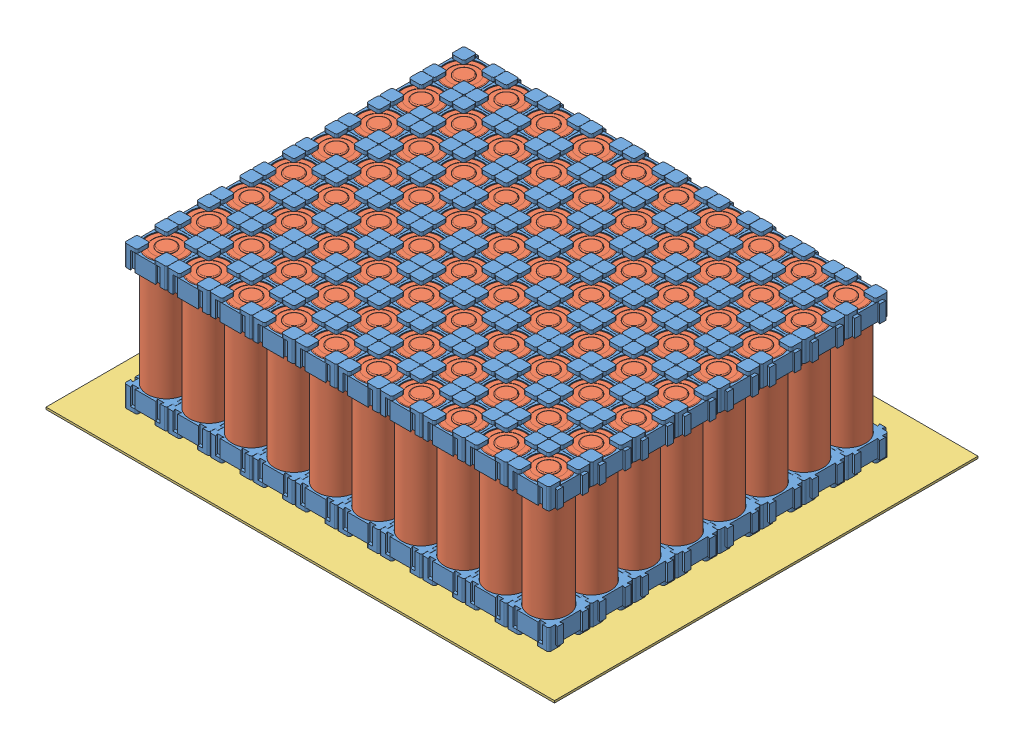
SolidWorks assembly BatteyPackOneLevel, configuration Default. Lengths in mm.
Overall size (245.5 69.3 204.9).
321 component instances, 3 part files, 4 mates.
Components (placement in the parent):
- SingleCellAssembly-2: SingleCellAssembly [Default] at (-432.012 -66.15 -21.6) x (0 0 1) z (1 0 0) size (21.6 68.3 21.6)
  - 1P Holder-1: 1P Holder [Default] at (11.5 -56.15 60.678) x (0 0 -1) z (-1 0 0) size (21.6 10 21.6)
  - 1P Holder-2: 1P Holder [Default] at (11.5 -7.85 60.678) size (21.6 10 21.6)
  - 18650 battery-2: 18650 battery [默认] at (40.3744 0.35 45.406) x (1 0 0) z (0 -1 0) size (18.2 18.2 65.15)
- SingleCellAssembly-374: SingleCellAssembly [Default] at (-411.712 -66.15 -21.6) x (0 0 1) z (1 0 0) size (21.6 68.3 21.6)
  - 1P Holder-1: 1P Holder [Default] at (11.5 -56.15 60.678) x (0 0 -1) z (-1 0 0) size (21.6 10 21.6)
  - 1P Holder-2: 1P Holder [Default] at (11.5 -7.85 60.678) size (21.6 10 21.6)
  - 18650 battery-2: 18650 battery [默认] at (40.3744 0.35 45.406) x (1 0 0) z (0 -1 0) size (18.2 18.2 65.15)
- SingleCellAssembly-375: SingleCellAssembly [Default] at (-391.412 -66.15 -21.6) x (0 0 1) z (1 0 0) size (21.6 68.3 21.6)
  - 1P Holder-1: 1P Holder [Default] at (11.5 -56.15 60.678) x (0 0 -1) z (-1 0 0) size (21.6 10 21.6)
  - 1P Holder-2: 1P Holder [Default] at (11.5 -7.85 60.678) size (21.6 10 21.6)
  - 18650 battery-2: 18650 battery [默认] at (40.3744 0.35 45.406) x (1 0 0) z (0 -1 0) size (18.2 18.2 65.15)
- SingleCellAssembly-376: SingleCellAssembly [Default] at (-371.112 -66.15 -21.6) x (0 0 1) z (1 0 0) size (21.6 68.3 21.6)
  - 1P Holder-1: 1P Holder [Default] at (11.5 -56.15 60.678) x (0 0 -1) z (-1 0 0) size (21.6 10 21.6)
  - 1P Holder-2: 1P Holder [Default] at (11.5 -7.85 60.678) size (21.6 10 21.6)
  - 18650 battery-2: 18650 battery [默认] at (40.3744 0.35 45.406) x (1 0 0) z (0 -1 0) size (18.2 18.2 65.15)
- SingleCellAssembly-377: SingleCellAssembly [Default] at (-350.812 -66.15 -21.6) x (0 0 1) z (1 0 0) size (21.6 68.3 21.6)
  - 1P Holder-1: 1P Holder [Default] at (11.5 -56.15 60.678) x (0 0 -1) z (-1 0 0) size (21.6 10 21.6)
  - 1P Holder-2: 1P Holder [Default] at (11.5 -7.85 60.678) size (21.6 10 21.6)
  - 18650 battery-2: 18650 battery [默认] at (40.3744 0.35 45.406) x (1 0 0) z (0 -1 0) size (18.2 18.2 65.15)
- SingleCellAssembly-378: SingleCellAssembly [Default] at (-330.512 -66.15 -21.6) x (0 0 1) z (1 0 0) size (21.6 68.3 21.6)
  - 1P Holder-1: 1P Holder [Default] at (11.5 -56.15 60.678) x (0 0 -1) z (-1 0 0) size (21.6 10 21.6)
  - 1P Holder-2: 1P Holder [Default] at (11.5 -7.85 60.678) size (21.6 10 21.6)
  - 18650 battery-2: 18650 battery [默认] at (40.3744 0.35 45.406) x (1 0 0) z (0 -1 0) size (18.2 18.2 65.15)
- SingleCellAssembly-379: SingleCellAssembly [Default] at (-310.212 -66.15 -21.6) x (0 0 1) z (1 0 0) size (21.6 68.3 21.6)
  - 1P Holder-1: 1P Holder [Default] at (11.5 -56.15 60.678) x (0 0 -1) z (-1 0 0) size (21.6 10 21.6)
  - 1P Holder-2: 1P Holder [Default] at (11.5 -7.85 60.678) size (21.6 10 21.6)
  - 18650 battery-2: 18650 battery [默认] at (40.3744 0.35 45.406) x (1 0 0) z (0 -1 0) size (18.2 18.2 65.15)
- SingleCellAssembly-380: SingleCellAssembly [Default] at (-289.912 -66.15 -21.6) x (0 0 1) z (1 0 0) size (21.6 68.3 21.6)
  - 1P Holder-1: 1P Holder [Default] at (11.5 -56.15 60.678) x (0 0 -1) z (-1 0 0) size (21.6 10 21.6)
  - 1P Holder-2: 1P Holder [Default] at (11.5 -7.85 60.678) size (21.6 10 21.6)
  - 18650 battery-2: 18650 battery [默认] at (40.3744 0.35 45.406) x (1 0 0) z (0 -1 0) size (18.2 18.2 65.15)
- SingleCellAssembly-381: SingleCellAssembly [Default] at (-269.612 -66.15 -21.6) x (0 0 1) z (1 0 0) size (21.6 68.3 21.6)
  - 1P Holder-1: 1P Holder [Default] at (11.5 -56.15 60.678) x (0 0 -1) z (-1 0 0) size (21.6 10 21.6)
  - 1P Holder-2: 1P Holder [Default] at (11.5 -7.85 60.678) size (21.6 10 21.6)
  - 18650 battery-2: 18650 battery [默认] at (40.3744 0.35 45.406) x (1 0 0) z (0 -1 0) size (18.2 18.2 65.15)
- SingleCellAssembly-382: SingleCellAssembly [Default] at (-249.312 -66.15 -21.6) x (0 0 1) z (1 0 0) size (21.6 68.3 21.6)
  - 1P Holder-1: 1P Holder [Default] at (11.5 -56.15 60.678) x (0 0 -1) z (-1 0 0) size (21.6 10 21.6)
  - 1P Holder-2: 1P Holder [Default] at (11.5 -7.85 60.678) size (21.6 10 21.6)
  - 18650 battery-2: 18650 battery [默认] at (40.3744 0.35 45.406) x (1 0 0) z (0 -1 0) size (18.2 18.2 65.15)
- BatteryCase-1: BatteryCase [Default] at (413.8437 -69.3 344.5858) size (245.5 1 204.9)
- SingleCellAssembly-703: SingleCellAssembly [Default] at (-432.012 -66.15 -41.9) x (0 0 1) z (1 0 0) size (21.6 68.3 21.6)
  - 1P Holder-1: 1P Holder [Default] at (11.5 -56.15 60.678) x (0 0 -1) z (-1 0 0) size (21.6 10 21.6)
  - 1P Holder-2: 1P Holder [Default] at (11.5 -7.85 60.678) size (21.6 10 21.6)
  - 18650 battery-2: 18650 battery [默认] at (40.3744 0.35 45.406) x (1 0 0) z (0 -1 0) size (18.2 18.2 65.15)
- SingleCellAssembly-704: SingleCellAssembly [Default] at (-432.012 -66.15 -62.2) x (0 0 1) z (1 0 0) size (21.6 68.3 21.6)
  - 1P Holder-1: 1P Holder [Default] at (11.5 -56.15 60.678) x (0 0 -1) z (-1 0 0) size (21.6 10 21.6)
  - 1P Holder-2: 1P Holder [Default] at (11.5 -7.85 60.678) size (21.6 10 21.6)
  - 18650 battery-2: 18650 battery [默认] at (40.3744 0.35 45.406) x (1 0 0) z (0 -1 0) size (18.2 18.2 65.15)
- SingleCellAssembly-705: SingleCellAssembly [Default] at (-432.012 -66.15 -82.5) x (0 0 1) z (1 0 0) size (21.6 68.3 21.6)
  - 1P Holder-1: 1P Holder [Default] at (11.5 -56.15 60.678) x (0 0 -1) z (-1 0 0) size (21.6 10 21.6)
  - 1P Holder-2: 1P Holder [Default] at (11.5 -7.85 60.678) size (21.6 10 21.6)
  - 18650 battery-2: 18650 battery [默认] at (40.3744 0.35 45.406) x (1 0 0) z (0 -1 0) size (18.2 18.2 65.15)
- SingleCellAssembly-706: SingleCellAssembly [Default] at (-432.012 -66.15 -102.8) x (0 0 1) z (1 0 0) size (21.6 68.3 21.6)
  - 1P Holder-1: 1P Holder [Default] at (11.5 -56.15 60.678) x (0 0 -1) z (-1 0 0) size (21.6 10 21.6)
  - 1P Holder-2: 1P Holder [Default] at (11.5 -7.85 60.678) size (21.6 10 21.6)
  - 18650 battery-2: 18650 battery [默认] at (40.3744 0.35 45.406) x (1 0 0) z (0 -1 0) size (18.2 18.2 65.15)
- SingleCellAssembly-707: SingleCellAssembly [Default] at (-432.012 -66.15 -123.1) x (0 0 1) z (1 0 0) size (21.6 68.3 21.6)
  - 1P Holder-1: 1P Holder [Default] at (11.5 -56.15 60.678) x (0 0 -1) z (-1 0 0) size (21.6 10 21.6)
  - 1P Holder-2: 1P Holder [Default] at (11.5 -7.85 60.678) size (21.6 10 21.6)
  - 18650 battery-2: 18650 battery [默认] at (40.3744 0.35 45.406) x (1 0 0) z (0 -1 0) size (18.2 18.2 65.15)
- SingleCellAssembly-708: SingleCellAssembly [Default] at (-432.012 -66.15 -143.4) x (0 0 1) z (1 0 0) size (21.6 68.3 21.6)
  - 1P Holder-1: 1P Holder [Default] at (11.5 -56.15 60.678) x (0 0 -1) z (-1 0 0) size (21.6 10 21.6)
  - 1P Holder-2: 1P Holder [Default] at (11.5 -7.85 60.678) size (21.6 10 21.6)
  - 18650 battery-2: 18650 battery [默认] at (40.3744 0.35 45.406) x (1 0 0) z (0 -1 0) size (18.2 18.2 65.15)
- SingleCellAssembly-709: SingleCellAssembly [Default] at (-432.012 -66.15 -163.7) x (0 0 1) z (1 0 0) size (21.6 68.3 21.6)
  - 1P Holder-1: 1P Holder [Default] at (11.5 -56.15 60.678) x (0 0 -1) z (-1 0 0) size (21.6 10 21.6)
  - 1P Holder-2: 1P Holder [Default] at (11.5 -7.85 60.678) size (21.6 10 21.6)
  - 18650 battery-2: 18650 battery [默认] at (40.3744 0.35 45.406) x (1 0 0) z (0 -1 0) size (18.2 18.2 65.15)
- SingleCellAssembly-710: SingleCellAssembly [Default] at (-411.712 -66.15 -41.9) x (0 0 1) z (1 0 0) size (21.6 68.3 21.6)
  - 1P Holder-1: 1P Holder [Default] at (11.5 -56.15 60.678) x (0 0 -1) z (-1 0 0) size (21.6 10 21.6)
  - 1P Holder-2: 1P Holder [Default] at (11.5 -7.85 60.678) size (21.6 10 21.6)
  - 18650 battery-2: 18650 battery [默认] at (40.3744 0.35 45.406) x (1 0 0) z (0 -1 0) size (18.2 18.2 65.15)
- SingleCellAssembly-711: SingleCellAssembly [Default] at (-411.712 -66.15 -62.2) x (0 0 1) z (1 0 0) size (21.6 68.3 21.6)
  - 1P Holder-1: 1P Holder [Default] at (11.5 -56.15 60.678) x (0 0 -1) z (-1 0 0) size (21.6 10 21.6)
  - 1P Holder-2: 1P Holder [Default] at (11.5 -7.85 60.678) size (21.6 10 21.6)
  - 18650 battery-2: 18650 battery [默认] at (40.3744 0.35 45.406) x (1 0 0) z (0 -1 0) size (18.2 18.2 65.15)
- SingleCellAssembly-712: SingleCellAssembly [Default] at (-411.712 -66.15 -82.5) x (0 0 1) z (1 0 0) size (21.6 68.3 21.6)
  - 1P Holder-1: 1P Holder [Default] at (11.5 -56.15 60.678) x (0 0 -1) z (-1 0 0) size (21.6 10 21.6)
  - 1P Holder-2: 1P Holder [Default] at (11.5 -7.85 60.678) size (21.6 10 21.6)
  - 18650 battery-2: 18650 battery [默认] at (40.3744 0.35 45.406) x (1 0 0) z (0 -1 0) size (18.2 18.2 65.15)
- SingleCellAssembly-713: SingleCellAssembly [Default] at (-411.712 -66.15 -102.8) x (0 0 1) z (1 0 0) size (21.6 68.3 21.6)
  - 1P Holder-1: 1P Holder [Default] at (11.5 -56.15 60.678) x (0 0 -1) z (-1 0 0) size (21.6 10 21.6)
  - 1P Holder-2: 1P Holder [Default] at (11.5 -7.85 60.678) size (21.6 10 21.6)
  - 18650 battery-2: 18650 battery [默认] at (40.3744 0.35 45.406) x (1 0 0) z (0 -1 0) size (18.2 18.2 65.15)
- SingleCellAssembly-714: SingleCellAssembly [Default] at (-411.712 -66.15 -123.1) x (0 0 1) z (1 0 0) size (21.6 68.3 21.6)
  - 1P Holder-1: 1P Holder [Default] at (11.5 -56.15 60.678) x (0 0 -1) z (-1 0 0) size (21.6 10 21.6)
  - 1P Holder-2: 1P Holder [Default] at (11.5 -7.85 60.678) size (21.6 10 21.6)
  - 18650 battery-2: 18650 battery [默认] at (40.3744 0.35 45.406) x (1 0 0) z (0 -1 0) size (18.2 18.2 65.15)
- SingleCellAssembly-715: SingleCellAssembly [Default] at (-411.712 -66.15 -143.4) x (0 0 1) z (1 0 0) size (21.6 68.3 21.6)
  - 1P Holder-1: 1P Holder [Default] at (11.5 -56.15 60.678) x (0 0 -1) z (-1 0 0) size (21.6 10 21.6)
  - 1P Holder-2: 1P Holder [Default] at (11.5 -7.85 60.678) size (21.6 10 21.6)
  - 18650 battery-2: 18650 battery [默认] at (40.3744 0.35 45.406) x (1 0 0) z (0 -1 0) size (18.2 18.2 65.15)
- SingleCellAssembly-716: SingleCellAssembly [Default] at (-411.712 -66.15 -163.7) x (0 0 1) z (1 0 0) size (21.6 68.3 21.6)
  - 1P Holder-1: 1P Holder [Default] at (11.5 -56.15 60.678) x (0 0 -1) z (-1 0 0) size (21.6 10 21.6)
  - 1P Holder-2: 1P Holder [Default] at (11.5 -7.85 60.678) size (21.6 10 21.6)
  - 18650 battery-2: 18650 battery [默认] at (40.3744 0.35 45.406) x (1 0 0) z (0 -1 0) size (18.2 18.2 65.15)
- SingleCellAssembly-717: SingleCellAssembly [Default] at (-391.412 -66.15 -41.9) x (0 0 1) z (1 0 0) size (21.6 68.3 21.6)
  - 1P Holder-1: 1P Holder [Default] at (11.5 -56.15 60.678) x (0 0 -1) z (-1 0 0) size (21.6 10 21.6)
  - 1P Holder-2: 1P Holder [Default] at (11.5 -7.85 60.678) size (21.6 10 21.6)
  - 18650 battery-2: 18650 battery [默认] at (40.3744 0.35 45.406) x (1 0 0) z (0 -1 0) size (18.2 18.2 65.15)
- SingleCellAssembly-718: SingleCellAssembly [Default] at (-391.412 -66.15 -62.2) x (0 0 1) z (1 0 0) size (21.6 68.3 21.6)
  - 1P Holder-1: 1P Holder [Default] at (11.5 -56.15 60.678) x (0 0 -1) z (-1 0 0) size (21.6 10 21.6)
  - 1P Holder-2: 1P Holder [Default] at (11.5 -7.85 60.678) size (21.6 10 21.6)
  - 18650 battery-2: 18650 battery [默认] at (40.3744 0.35 45.406) x (1 0 0) z (0 -1 0) size (18.2 18.2 65.15)
- SingleCellAssembly-719: SingleCellAssembly [Default] at (-391.412 -66.15 -82.5) x (0 0 1) z (1 0 0) size (21.6 68.3 21.6)
  - 1P Holder-1: 1P Holder [Default] at (11.5 -56.15 60.678) x (0 0 -1) z (-1 0 0) size (21.6 10 21.6)
  - 1P Holder-2: 1P Holder [Default] at (11.5 -7.85 60.678) size (21.6 10 21.6)
  - 18650 battery-2: 18650 battery [默认] at (40.3744 0.35 45.406) x (1 0 0) z (0 -1 0) size (18.2 18.2 65.15)
- SingleCellAssembly-720: SingleCellAssembly [Default] at (-391.412 -66.15 -102.8) x (0 0 1) z (1 0 0) size (21.6 68.3 21.6)
  - 1P Holder-1: 1P Holder [Default] at (11.5 -56.15 60.678) x (0 0 -1) z (-1 0 0) size (21.6 10 21.6)
  - 1P Holder-2: 1P Holder [Default] at (11.5 -7.85 60.678) size (21.6 10 21.6)
  - 18650 battery-2: 18650 battery [默认] at (40.3744 0.35 45.406) x (1 0 0) z (0 -1 0) size (18.2 18.2 65.15)
- SingleCellAssembly-721: SingleCellAssembly [Default] at (-391.412 -66.15 -123.1) x (0 0 1) z (1 0 0) size (21.6 68.3 21.6)
  - 1P Holder-1: 1P Holder [Default] at (11.5 -56.15 60.678) x (0 0 -1) z (-1 0 0) size (21.6 10 21.6)
  - 1P Holder-2: 1P Holder [Default] at (11.5 -7.85 60.678) size (21.6 10 21.6)
  - 18650 battery-2: 18650 battery [默认] at (40.3744 0.35 45.406) x (1 0 0) z (0 -1 0) size (18.2 18.2 65.15)
- SingleCellAssembly-722: SingleCellAssembly [Default] at (-391.412 -66.15 -143.4) x (0 0 1) z (1 0 0) size (21.6 68.3 21.6)
  - 1P Holder-1: 1P Holder [Default] at (11.5 -56.15 60.678) x (0 0 -1) z (-1 0 0) size (21.6 10 21.6)
  - 1P Holder-2: 1P Holder [Default] at (11.5 -7.85 60.678) size (21.6 10 21.6)
  - 18650 battery-2: 18650 battery [默认] at (40.3744 0.35 45.406) x (1 0 0) z (0 -1 0) size (18.2 18.2 65.15)
- SingleCellAssembly-723: SingleCellAssembly [Default] at (-391.412 -66.15 -163.7) x (0 0 1) z (1 0 0) size (21.6 68.3 21.6)
  - 1P Holder-1: 1P Holder [Default] at (11.5 -56.15 60.678) x (0 0 -1) z (-1 0 0) size (21.6 10 21.6)
  - 1P Holder-2: 1P Holder [Default] at (11.5 -7.85 60.678) size (21.6 10 21.6)
  - 18650 battery-2: 18650 battery [默认] at (40.3744 0.35 45.406) x (1 0 0) z (0 -1 0) size (18.2 18.2 65.15)
- SingleCellAssembly-724: SingleCellAssembly [Default] at (-371.112 -66.15 -41.9) x (0 0 1) z (1 0 0) size (21.6 68.3 21.6)
  - 1P Holder-1: 1P Holder [Default] at (11.5 -56.15 60.678) x (0 0 -1) z (-1 0 0) size (21.6 10 21.6)
  - 1P Holder-2: 1P Holder [Default] at (11.5 -7.85 60.678) size (21.6 10 21.6)
  - 18650 battery-2: 18650 battery [默认] at (40.3744 0.35 45.406) x (1 0 0) z (0 -1 0) size (18.2 18.2 65.15)
- SingleCellAssembly-725: SingleCellAssembly [Default] at (-371.112 -66.15 -62.2) x (0 0 1) z (1 0 0) size (21.6 68.3 21.6)
  - 1P Holder-1: 1P Holder [Default] at (11.5 -56.15 60.678) x (0 0 -1) z (-1 0 0) size (21.6 10 21.6)
  - 1P Holder-2: 1P Holder [Default] at (11.5 -7.85 60.678) size (21.6 10 21.6)
  - 18650 battery-2: 18650 battery [默认] at (40.3744 0.35 45.406) x (1 0 0) z (0 -1 0) size (18.2 18.2 65.15)
- SingleCellAssembly-726: SingleCellAssembly [Default] at (-371.112 -66.15 -82.5) x (0 0 1) z (1 0 0) size (21.6 68.3 21.6)
  - 1P Holder-1: 1P Holder [Default] at (11.5 -56.15 60.678) x (0 0 -1) z (-1 0 0) size (21.6 10 21.6)
  - 1P Holder-2: 1P Holder [Default] at (11.5 -7.85 60.678) size (21.6 10 21.6)
  - 18650 battery-2: 18650 battery [默认] at (40.3744 0.35 45.406) x (1 0 0) z (0 -1 0) size (18.2 18.2 65.15)
- SingleCellAssembly-727: SingleCellAssembly [Default] at (-371.112 -66.15 -102.8) x (0 0 1) z (1 0 0) size (21.6 68.3 21.6)
  - 1P Holder-1: 1P Holder [Default] at (11.5 -56.15 60.678) x (0 0 -1) z (-1 0 0) size (21.6 10 21.6)
  - 1P Holder-2: 1P Holder [Default] at (11.5 -7.85 60.678) size (21.6 10 21.6)
  - 18650 battery-2: 18650 battery [默认] at (40.3744 0.35 45.406) x (1 0 0) z (0 -1 0) size (18.2 18.2 65.15)
- SingleCellAssembly-728: SingleCellAssembly [Default] at (-371.112 -66.15 -123.1) x (0 0 1) z (1 0 0) size (21.6 68.3 21.6)
  - 1P Holder-1: 1P Holder [Default] at (11.5 -56.15 60.678) x (0 0 -1) z (-1 0 0) size (21.6 10 21.6)
  - 1P Holder-2: 1P Holder [Default] at (11.5 -7.85 60.678) size (21.6 10 21.6)
  - 18650 battery-2: 18650 battery [默认] at (40.3744 0.35 45.406) x (1 0 0) z (0 -1 0) size (18.2 18.2 65.15)
- SingleCellAssembly-729: SingleCellAssembly [Default] at (-371.112 -66.15 -143.4) x (0 0 1) z (1 0 0) size (21.6 68.3 21.6)
  - 1P Holder-1: 1P Holder [Default] at (11.5 -56.15 60.678) x (0 0 -1) z (-1 0 0) size (21.6 10 21.6)
  - 1P Holder-2: 1P Holder [Default] at (11.5 -7.85 60.678) size (21.6 10 21.6)
  - 18650 battery-2: 18650 battery [默认] at (40.3744 0.35 45.406) x (1 0 0) z (0 -1 0) size (18.2 18.2 65.15)
- SingleCellAssembly-730: SingleCellAssembly [Default] at (-371.112 -66.15 -163.7) x (0 0 1) z (1 0 0) size (21.6 68.3 21.6)
  - 1P Holder-1: 1P Holder [Default] at (11.5 -56.15 60.678) x (0 0 -1) z (-1 0 0) size (21.6 10 21.6)
  - 1P Holder-2: 1P Holder [Default] at (11.5 -7.85 60.678) size (21.6 10 21.6)
  - 18650 battery-2: 18650 battery [默认] at (40.3744 0.35 45.406) x (1 0 0) z (0 -1 0) size (18.2 18.2 65.15)
- SingleCellAssembly-731: SingleCellAssembly [Default] at (-350.812 -66.15 -41.9) x (0 0 1) z (1 0 0) size (21.6 68.3 21.6)
  - 1P Holder-1: 1P Holder [Default] at (11.5 -56.15 60.678) x (0 0 -1) z (-1 0 0) size (21.6 10 21.6)
  - 1P Holder-2: 1P Holder [Default] at (11.5 -7.85 60.678) size (21.6 10 21.6)
  - 18650 battery-2: 18650 battery [默认] at (40.3744 0.35 45.406) x (1 0 0) z (0 -1 0) size (18.2 18.2 65.15)
- SingleCellAssembly-732: SingleCellAssembly [Default] at (-350.812 -66.15 -62.2) x (0 0 1) z (1 0 0) size (21.6 68.3 21.6)
  - 1P Holder-1: 1P Holder [Default] at (11.5 -56.15 60.678) x (0 0 -1) z (-1 0 0) size (21.6 10 21.6)
  - 1P Holder-2: 1P Holder [Default] at (11.5 -7.85 60.678) size (21.6 10 21.6)
  - 18650 battery-2: 18650 battery [默认] at (40.3744 0.35 45.406) x (1 0 0) z (0 -1 0) size (18.2 18.2 65.15)
- SingleCellAssembly-733: SingleCellAssembly [Default] at (-350.812 -66.15 -82.5) x (0 0 1) z (1 0 0) size (21.6 68.3 21.6)
  - 1P Holder-1: 1P Holder [Default] at (11.5 -56.15 60.678) x (0 0 -1) z (-1 0 0) size (21.6 10 21.6)
  - 1P Holder-2: 1P Holder [Default] at (11.5 -7.85 60.678) size (21.6 10 21.6)
  - 18650 battery-2: 18650 battery [默认] at (40.3744 0.35 45.406) x (1 0 0) z (0 -1 0) size (18.2 18.2 65.15)
- SingleCellAssembly-734: SingleCellAssembly [Default] at (-350.812 -66.15 -102.8) x (0 0 1) z (1 0 0) size (21.6 68.3 21.6)
  - 1P Holder-1: 1P Holder [Default] at (11.5 -56.15 60.678) x (0 0 -1) z (-1 0 0) size (21.6 10 21.6)
  - 1P Holder-2: 1P Holder [Default] at (11.5 -7.85 60.678) size (21.6 10 21.6)
  - 18650 battery-2: 18650 battery [默认] at (40.3744 0.35 45.406) x (1 0 0) z (0 -1 0) size (18.2 18.2 65.15)
- SingleCellAssembly-735: SingleCellAssembly [Default] at (-350.812 -66.15 -123.1) x (0 0 1) z (1 0 0) size (21.6 68.3 21.6)
  - 1P Holder-1: 1P Holder [Default] at (11.5 -56.15 60.678) x (0 0 -1) z (-1 0 0) size (21.6 10 21.6)
  - 1P Holder-2: 1P Holder [Default] at (11.5 -7.85 60.678) size (21.6 10 21.6)
  - 18650 battery-2: 18650 battery [默认] at (40.3744 0.35 45.406) x (1 0 0) z (0 -1 0) size (18.2 18.2 65.15)
- SingleCellAssembly-736: SingleCellAssembly [Default] at (-350.812 -66.15 -143.4) x (0 0 1) z (1 0 0) size (21.6 68.3 21.6)
  - 1P Holder-1: 1P Holder [Default] at (11.5 -56.15 60.678) x (0 0 -1) z (-1 0 0) size (21.6 10 21.6)
  - 1P Holder-2: 1P Holder [Default] at (11.5 -7.85 60.678) size (21.6 10 21.6)
  - 18650 battery-2: 18650 battery [默认] at (40.3744 0.35 45.406) x (1 0 0) z (0 -1 0) size (18.2 18.2 65.15)
- SingleCellAssembly-737: SingleCellAssembly [Default] at (-350.812 -66.15 -163.7) x (0 0 1) z (1 0 0) size (21.6 68.3 21.6)
  - 1P Holder-1: 1P Holder [Default] at (11.5 -56.15 60.678) x (0 0 -1) z (-1 0 0) size (21.6 10 21.6)
  - 1P Holder-2: 1P Holder [Default] at (11.5 -7.85 60.678) size (21.6 10 21.6)
  - 18650 battery-2: 18650 battery [默认] at (40.3744 0.35 45.406) x (1 0 0) z (0 -1 0) size (18.2 18.2 65.15)
- SingleCellAssembly-738: SingleCellAssembly [Default] at (-330.512 -66.15 -41.9) x (0 0 1) z (1 0 0) size (21.6 68.3 21.6)
  - 1P Holder-1: 1P Holder [Default] at (11.5 -56.15 60.678) x (0 0 -1) z (-1 0 0) size (21.6 10 21.6)
  - 1P Holder-2: 1P Holder [Default] at (11.5 -7.85 60.678) size (21.6 10 21.6)
  - 18650 battery-2: 18650 battery [默认] at (40.3744 0.35 45.406) x (1 0 0) z (0 -1 0) size (18.2 18.2 65.15)
- SingleCellAssembly-739: SingleCellAssembly [Default] at (-330.512 -66.15 -62.2) x (0 0 1) z (1 0 0) size (21.6 68.3 21.6)
  - 1P Holder-1: 1P Holder [Default] at (11.5 -56.15 60.678) x (0 0 -1) z (-1 0 0) size (21.6 10 21.6)
  - 1P Holder-2: 1P Holder [Default] at (11.5 -7.85 60.678) size (21.6 10 21.6)
  - 18650 battery-2: 18650 battery [默认] at (40.3744 0.35 45.406) x (1 0 0) z (0 -1 0) size (18.2 18.2 65.15)
- SingleCellAssembly-740: SingleCellAssembly [Default] at (-330.512 -66.15 -82.5) x (0 0 1) z (1 0 0) size (21.6 68.3 21.6)
  - 1P Holder-1: 1P Holder [Default] at (11.5 -56.15 60.678) x (0 0 -1) z (-1 0 0) size (21.6 10 21.6)
  - 1P Holder-2: 1P Holder [Default] at (11.5 -7.85 60.678) size (21.6 10 21.6)
  - 18650 battery-2: 18650 battery [默认] at (40.3744 0.35 45.406) x (1 0 0) z (0 -1 0) size (18.2 18.2 65.15)
- SingleCellAssembly-741: SingleCellAssembly [Default] at (-330.512 -66.15 -102.8) x (0 0 1) z (1 0 0) size (21.6 68.3 21.6)
  - 1P Holder-1: 1P Holder [Default] at (11.5 -56.15 60.678) x (0 0 -1) z (-1 0 0) size (21.6 10 21.6)
  - 1P Holder-2: 1P Holder [Default] at (11.5 -7.85 60.678) size (21.6 10 21.6)
  - 18650 battery-2: 18650 battery [默认] at (40.3744 0.35 45.406) x (1 0 0) z (0 -1 0) size (18.2 18.2 65.15)
- SingleCellAssembly-742: SingleCellAssembly [Default] at (-330.512 -66.15 -123.1) x (0 0 1) z (1 0 0) size (21.6 68.3 21.6)
  - 1P Holder-1: 1P Holder [Default] at (11.5 -56.15 60.678) x (0 0 -1) z (-1 0 0) size (21.6 10 21.6)
  - 1P Holder-2: 1P Holder [Default] at (11.5 -7.85 60.678) size (21.6 10 21.6)
  - 18650 battery-2: 18650 battery [默认] at (40.3744 0.35 45.406) x (1 0 0) z (0 -1 0) size (18.2 18.2 65.15)
- SingleCellAssembly-743: SingleCellAssembly [Default] at (-330.512 -66.15 -143.4) x (0 0 1) z (1 0 0) size (21.6 68.3 21.6)
  - 1P Holder-1: 1P Holder [Default] at (11.5 -56.15 60.678) x (0 0 -1) z (-1 0 0) size (21.6 10 21.6)
  - 1P Holder-2: 1P Holder [Default] at (11.5 -7.85 60.678) size (21.6 10 21.6)
  - 18650 battery-2: 18650 battery [默认] at (40.3744 0.35 45.406) x (1 0 0) z (0 -1 0) size (18.2 18.2 65.15)
- SingleCellAssembly-744: SingleCellAssembly [Default] at (-330.512 -66.15 -163.7) x (0 0 1) z (1 0 0) size (21.6 68.3 21.6)
  - 1P Holder-1: 1P Holder [Default] at (11.5 -56.15 60.678) x (0 0 -1) z (-1 0 0) size (21.6 10 21.6)
  - 1P Holder-2: 1P Holder [Default] at (11.5 -7.85 60.678) size (21.6 10 21.6)
  - 18650 battery-2: 18650 battery [默认] at (40.3744 0.35 45.406) x (1 0 0) z (0 -1 0) size (18.2 18.2 65.15)
- SingleCellAssembly-745: SingleCellAssembly [Default] at (-310.212 -66.15 -41.9) x (0 0 1) z (1 0 0) size (21.6 68.3 21.6)
  - 1P Holder-1: 1P Holder [Default] at (11.5 -56.15 60.678) x (0 0 -1) z (-1 0 0) size (21.6 10 21.6)
  - 1P Holder-2: 1P Holder [Default] at (11.5 -7.85 60.678) size (21.6 10 21.6)
  - 18650 battery-2: 18650 battery [默认] at (40.3744 0.35 45.406) x (1 0 0) z (0 -1 0) size (18.2 18.2 65.15)
- SingleCellAssembly-746: SingleCellAssembly [Default] at (-310.212 -66.15 -62.2) x (0 0 1) z (1 0 0) size (21.6 68.3 21.6)
  - 1P Holder-1: 1P Holder [Default] at (11.5 -56.15 60.678) x (0 0 -1) z (-1 0 0) size (21.6 10 21.6)
  - 1P Holder-2: 1P Holder [Default] at (11.5 -7.85 60.678) size (21.6 10 21.6)
  - 18650 battery-2: 18650 battery [默认] at (40.3744 0.35 45.406) x (1 0 0) z (0 -1 0) size (18.2 18.2 65.15)
- SingleCellAssembly-747: SingleCellAssembly [Default] at (-310.212 -66.15 -82.5) x (0 0 1) z (1 0 0) size (21.6 68.3 21.6)
  - 1P Holder-1: 1P Holder [Default] at (11.5 -56.15 60.678) x (0 0 -1) z (-1 0 0) size (21.6 10 21.6)
  - 1P Holder-2: 1P Holder [Default] at (11.5 -7.85 60.678) size (21.6 10 21.6)
  - 18650 battery-2: 18650 battery [默认] at (40.3744 0.35 45.406) x (1 0 0) z (0 -1 0) size (18.2 18.2 65.15)
- SingleCellAssembly-748: SingleCellAssembly [Default] at (-310.212 -66.15 -102.8) x (0 0 1) z (1 0 0) size (21.6 68.3 21.6)
  - 1P Holder-1: 1P Holder [Default] at (11.5 -56.15 60.678) x (0 0 -1) z (-1 0 0) size (21.6 10 21.6)
  - 1P Holder-2: 1P Holder [Default] at (11.5 -7.85 60.678) size (21.6 10 21.6)
  - 18650 battery-2: 18650 battery [默认] at (40.3744 0.35 45.406) x (1 0 0) z (0 -1 0) size (18.2 18.2 65.15)
- SingleCellAssembly-749: SingleCellAssembly [Default] at (-310.212 -66.15 -123.1) x (0 0 1) z (1 0 0) size (21.6 68.3 21.6)
  - 1P Holder-1: 1P Holder [Default] at (11.5 -56.15 60.678) x (0 0 -1) z (-1 0 0) size (21.6 10 21.6)
  - 1P Holder-2: 1P Holder [Default] at (11.5 -7.85 60.678) size (21.6 10 21.6)
  - 18650 battery-2: 18650 battery [默认] at (40.3744 0.35 45.406) x (1 0 0) z (0 -1 0) size (18.2 18.2 65.15)
- SingleCellAssembly-750: SingleCellAssembly [Default] at (-310.212 -66.15 -143.4) x (0 0 1) z (1 0 0) size (21.6 68.3 21.6)
  - 1P Holder-1: 1P Holder [Default] at (11.5 -56.15 60.678) x (0 0 -1) z (-1 0 0) size (21.6 10 21.6)
  - 1P Holder-2: 1P Holder [Default] at (11.5 -7.85 60.678) size (21.6 10 21.6)
  - 18650 battery-2: 18650 battery [默认] at (40.3744 0.35 45.406) x (1 0 0) z (0 -1 0) size (18.2 18.2 65.15)
- SingleCellAssembly-751: SingleCellAssembly [Default] at (-310.212 -66.15 -163.7) x (0 0 1) z (1 0 0) size (21.6 68.3 21.6)
  - 1P Holder-1: 1P Holder [Default] at (11.5 -56.15 60.678) x (0 0 -1) z (-1 0 0) size (21.6 10 21.6)
  - 1P Holder-2: 1P Holder [Default] at (11.5 -7.85 60.678) size (21.6 10 21.6)
  - 18650 battery-2: 18650 battery [默认] at (40.3744 0.35 45.406) x (1 0 0) z (0 -1 0) size (18.2 18.2 65.15)
- SingleCellAssembly-752: SingleCellAssembly [Default] at (-289.912 -66.15 -41.9) x (0 0 1) z (1 0 0) size (21.6 68.3 21.6)
  - 1P Holder-1: 1P Holder [Default] at (11.5 -56.15 60.678) x (0 0 -1) z (-1 0 0) size (21.6 10 21.6)
  - 1P Holder-2: 1P Holder [Default] at (11.5 -7.85 60.678) size (21.6 10 21.6)
  - 18650 battery-2: 18650 battery [默认] at (40.3744 0.35 45.406) x (1 0 0) z (0 -1 0) size (18.2 18.2 65.15)
- SingleCellAssembly-753: SingleCellAssembly [Default] at (-289.912 -66.15 -62.2) x (0 0 1) z (1 0 0) size (21.6 68.3 21.6)
  - 1P Holder-1: 1P Holder [Default] at (11.5 -56.15 60.678) x (0 0 -1) z (-1 0 0) size (21.6 10 21.6)
  - 1P Holder-2: 1P Holder [Default] at (11.5 -7.85 60.678) size (21.6 10 21.6)
  - 18650 battery-2: 18650 battery [默认] at (40.3744 0.35 45.406) x (1 0 0) z (0 -1 0) size (18.2 18.2 65.15)
- SingleCellAssembly-754: SingleCellAssembly [Default] at (-289.912 -66.15 -82.5) x (0 0 1) z (1 0 0) size (21.6 68.3 21.6)
  - 1P Holder-1: 1P Holder [Default] at (11.5 -56.15 60.678) x (0 0 -1) z (-1 0 0) size (21.6 10 21.6)
  - 1P Holder-2: 1P Holder [Default] at (11.5 -7.85 60.678) size (21.6 10 21.6)
  - 18650 battery-2: 18650 battery [默认] at (40.3744 0.35 45.406) x (1 0 0) z (0 -1 0) size (18.2 18.2 65.15)
- SingleCellAssembly-755: SingleCellAssembly [Default] at (-289.912 -66.15 -102.8) x (0 0 1) z (1 0 0) size (21.6 68.3 21.6)
  - 1P Holder-1: 1P Holder [Default] at (11.5 -56.15 60.678) x (0 0 -1) z (-1 0 0) size (21.6 10 21.6)
  - 1P Holder-2: 1P Holder [Default] at (11.5 -7.85 60.678) size (21.6 10 21.6)
  - 18650 battery-2: 18650 battery [默认] at (40.3744 0.35 45.406) x (1 0 0) z (0 -1 0) size (18.2 18.2 65.15)
- SingleCellAssembly-756: SingleCellAssembly [Default] at (-289.912 -66.15 -123.1) x (0 0 1) z (1 0 0) size (21.6 68.3 21.6)
  - 1P Holder-1: 1P Holder [Default] at (11.5 -56.15 60.678) x (0 0 -1) z (-1 0 0) size (21.6 10 21.6)
  - 1P Holder-2: 1P Holder [Default] at (11.5 -7.85 60.678) size (21.6 10 21.6)
  - 18650 battery-2: 18650 battery [默认] at (40.3744 0.35 45.406) x (1 0 0) z (0 -1 0) size (18.2 18.2 65.15)
- SingleCellAssembly-757: SingleCellAssembly [Default] at (-289.912 -66.15 -143.4) x (0 0 1) z (1 0 0) size (21.6 68.3 21.6)
  - 1P Holder-1: 1P Holder [Default] at (11.5 -56.15 60.678) x (0 0 -1) z (-1 0 0) size (21.6 10 21.6)
  - 1P Holder-2: 1P Holder [Default] at (11.5 -7.85 60.678) size (21.6 10 21.6)
  - 18650 battery-2: 18650 battery [默认] at (40.3744 0.35 45.406) x (1 0 0) z (0 -1 0) size (18.2 18.2 65.15)
- SingleCellAssembly-758: SingleCellAssembly [Default] at (-289.912 -66.15 -163.7) x (0 0 1) z (1 0 0) size (21.6 68.3 21.6)
  - 1P Holder-1: 1P Holder [Default] at (11.5 -56.15 60.678) x (0 0 -1) z (-1 0 0) size (21.6 10 21.6)
  - 1P Holder-2: 1P Holder [Default] at (11.5 -7.85 60.678) size (21.6 10 21.6)
  - 18650 battery-2: 18650 battery [默认] at (40.3744 0.35 45.406) x (1 0 0) z (0 -1 0) size (18.2 18.2 65.15)
- SingleCellAssembly-759: SingleCellAssembly [Default] at (-269.612 -66.15 -41.9) x (0 0 1) z (1 0 0) size (21.6 68.3 21.6)
  - 1P Holder-1: 1P Holder [Default] at (11.5 -56.15 60.678) x (0 0 -1) z (-1 0 0) size (21.6 10 21.6)
  - 1P Holder-2: 1P Holder [Default] at (11.5 -7.85 60.678) size (21.6 10 21.6)
  - 18650 battery-2: 18650 battery [默认] at (40.3744 0.35 45.406) x (1 0 0) z (0 -1 0) size (18.2 18.2 65.15)
- SingleCellAssembly-760: SingleCellAssembly [Default] at (-269.612 -66.15 -62.2) x (0 0 1) z (1 0 0) size (21.6 68.3 21.6)
  - 1P Holder-1: 1P Holder [Default] at (11.5 -56.15 60.678) x (0 0 -1) z (-1 0 0) size (21.6 10 21.6)
  - 1P Holder-2: 1P Holder [Default] at (11.5 -7.85 60.678) size (21.6 10 21.6)
  - 18650 battery-2: 18650 battery [默认] at (40.3744 0.35 45.406) x (1 0 0) z (0 -1 0) size (18.2 18.2 65.15)
- SingleCellAssembly-761: SingleCellAssembly [Default] at (-269.612 -66.15 -82.5) x (0 0 1) z (1 0 0) size (21.6 68.3 21.6)
  - 1P Holder-1: 1P Holder [Default] at (11.5 -56.15 60.678) x (0 0 -1) z (-1 0 0) size (21.6 10 21.6)
  - 1P Holder-2: 1P Holder [Default] at (11.5 -7.85 60.678) size (21.6 10 21.6)
  - 18650 battery-2: 18650 battery [默认] at (40.3744 0.35 45.406) x (1 0 0) z (0 -1 0) size (18.2 18.2 65.15)
- SingleCellAssembly-762: SingleCellAssembly [Default] at (-269.612 -66.15 -102.8) x (0 0 1) z (1 0 0) size (21.6 68.3 21.6)
  - 1P Holder-1: 1P Holder [Default] at (11.5 -56.15 60.678) x (0 0 -1) z (-1 0 0) size (21.6 10 21.6)
  - 1P Holder-2: 1P Holder [Default] at (11.5 -7.85 60.678) size (21.6 10 21.6)
  - 18650 battery-2: 18650 battery [默认] at (40.3744 0.35 45.406) x (1 0 0) z (0 -1 0) size (18.2 18.2 65.15)
- SingleCellAssembly-763: SingleCellAssembly [Default] at (-269.612 -66.15 -123.1) x (0 0 1) z (1 0 0) size (21.6 68.3 21.6)
  - 1P Holder-1: 1P Holder [Default] at (11.5 -56.15 60.678) x (0 0 -1) z (-1 0 0) size (21.6 10 21.6)
  - 1P Holder-2: 1P Holder [Default] at (11.5 -7.85 60.678) size (21.6 10 21.6)
  - 18650 battery-2: 18650 battery [默认] at (40.3744 0.35 45.406) x (1 0 0) z (0 -1 0) size (18.2 18.2 65.15)
- SingleCellAssembly-764: SingleCellAssembly [Default] at (-269.612 -66.15 -143.4) x (0 0 1) z (1 0 0) size (21.6 68.3 21.6)
  - 1P Holder-1: 1P Holder [Default] at (11.5 -56.15 60.678) x (0 0 -1) z (-1 0 0) size (21.6 10 21.6)
  - 1P Holder-2: 1P Holder [Default] at (11.5 -7.85 60.678) size (21.6 10 21.6)
  - 18650 battery-2: 18650 battery [默认] at (40.3744 0.35 45.406) x (1 0 0) z (0 -1 0) size (18.2 18.2 65.15)
- SingleCellAssembly-765: SingleCellAssembly [Default] at (-269.612 -66.15 -163.7) x (0 0 1) z (1 0 0) size (21.6 68.3 21.6)
  - 1P Holder-1: 1P Holder [Default] at (11.5 -56.15 60.678) x (0 0 -1) z (-1 0 0) size (21.6 10 21.6)
  - 1P Holder-2: 1P Holder [Default] at (11.5 -7.85 60.678) size (21.6 10 21.6)
  - 18650 battery-2: 18650 battery [默认] at (40.3744 0.35 45.406) x (1 0 0) z (0 -1 0) size (18.2 18.2 65.15)
- SingleCellAssembly-766: SingleCellAssembly [Default] at (-249.312 -66.15 -41.9) x (0 0 1) z (1 0 0) size (21.6 68.3 21.6)
  - 1P Holder-1: 1P Holder [Default] at (11.5 -56.15 60.678) x (0 0 -1) z (-1 0 0) size (21.6 10 21.6)
  - 1P Holder-2: 1P Holder [Default] at (11.5 -7.85 60.678) size (21.6 10 21.6)
  - 18650 battery-2: 18650 battery [默认] at (40.3744 0.35 45.406) x (1 0 0) z (0 -1 0) size (18.2 18.2 65.15)
- SingleCellAssembly-767: SingleCellAssembly [Default] at (-249.312 -66.15 -62.2) x (0 0 1) z (1 0 0) size (21.6 68.3 21.6)
  - 1P Holder-1: 1P Holder [Default] at (11.5 -56.15 60.678) x (0 0 -1) z (-1 0 0) size (21.6 10 21.6)
  - 1P Holder-2: 1P Holder [Default] at (11.5 -7.85 60.678) size (21.6 10 21.6)
  - 18650 battery-2: 18650 battery [默认] at (40.3744 0.35 45.406) x (1 0 0) z (0 -1 0) size (18.2 18.2 65.15)
- SingleCellAssembly-768: SingleCellAssembly [Default] at (-249.312 -66.15 -82.5) x (0 0 1) z (1 0 0) size (21.6 68.3 21.6)
  - 1P Holder-1: 1P Holder [Default] at (11.5 -56.15 60.678) x (0 0 -1) z (-1 0 0) size (21.6 10 21.6)
  - 1P Holder-2: 1P Holder [Default] at (11.5 -7.85 60.678) size (21.6 10 21.6)
  - 18650 battery-2: 18650 battery [默认] at (40.3744 0.35 45.406) x (1 0 0) z (0 -1 0) size (18.2 18.2 65.15)
- SingleCellAssembly-769: SingleCellAssembly [Default] at (-249.312 -66.15 -102.8) x (0 0 1) z (1 0 0) size (21.6 68.3 21.6)
  - 1P Holder-1: 1P Holder [Default] at (11.5 -56.15 60.678) x (0 0 -1) z (-1 0 0) size (21.6 10 21.6)
  - 1P Holder-2: 1P Holder [Default] at (11.5 -7.85 60.678) size (21.6 10 21.6)
  - 18650 battery-2: 18650 battery [默认] at (40.3744 0.35 45.406) x (1 0 0) z (0 -1 0) size (18.2 18.2 65.15)
- SingleCellAssembly-770: SingleCellAssembly [Default] at (-249.312 -66.15 -123.1) x (0 0 1) z (1 0 0) size (21.6 68.3 21.6)
  - 1P Holder-1: 1P Holder [Default] at (11.5 -56.15 60.678) x (0 0 -1) z (-1 0 0) size (21.6 10 21.6)
  - 1P Holder-2: 1P Holder [Default] at (11.5 -7.85 60.678) size (21.6 10 21.6)
  - 18650 battery-2: 18650 battery [默认] at (40.3744 0.35 45.406) x (1 0 0) z (0 -1 0) size (18.2 18.2 65.15)
- SingleCellAssembly-771: SingleCellAssembly [Default] at (-249.312 -66.15 -143.4) x (0 0 1) z (1 0 0) size (21.6 68.3 21.6)
  - 1P Holder-1: 1P Holder [Default] at (11.5 -56.15 60.678) x (0 0 -1) z (-1 0 0) size (21.6 10 21.6)
  - 1P Holder-2: 1P Holder [Default] at (11.5 -7.85 60.678) size (21.6 10 21.6)
  - 18650 battery-2: 18650 battery [默认] at (40.3744 0.35 45.406) x (1 0 0) z (0 -1 0) size (18.2 18.2 65.15)
- SingleCellAssembly-772: SingleCellAssembly [Default] at (-249.312 -66.15 -163.7) x (0 0 1) z (1 0 0) size (21.6 68.3 21.6)
  - 1P Holder-1: 1P Holder [Default] at (11.5 -56.15 60.678) x (0 0 -1) z (-1 0 0) size (21.6 10 21.6)
  - 1P Holder-2: 1P Holder [Default] at (11.5 -7.85 60.678) size (21.6 10 21.6)
  - 18650 battery-2: 18650 battery [默认] at (40.3744 0.35 45.406) x (1 0 0) z (0 -1 0) size (18.2 18.2 65.15)
Mates (geometry in assembly coordinates):
- Coincident1: coincident aligned: plane of SingleCellAssembly-2/1P Holder-1 through (-380.4341 0 -1) normal (0 1 0); plane of assembly through (0 0 0) normal (0 1 0)
- Coincident2: coincident aligned: plane of SingleCellAssembly-2/1P Holder-1 through (-366.3341 -1.8 0) normal (0 0 1); plane of assembly through (0 0 0) normal (0 0 1)
- Width1: width aligned: plane of BatteryCase-1 through (-400.9009 -68.8 15.05) normal (0 0 1); plane of BatteryCase-1 through (-400.9009 -68.8 -217.95) normal (0 0 -1); plane of SingleCellAssembly-378/1P Holder-2 through (-291.3009 -66.5 0) normal (0 0 1); plane of ? through (-250.7009 -66.5 -304.4) normal (0 0 -1)
- Coincident4: coincident anti-aligned: plane of SingleCellAssembly-2/1P Holder-2 through (-366.3341 -68.3 -5.1) normal (0 -1 0); plane of BatteryCase-1 through (413.8437 -68.3 344.5858) normal (0 1 0)
